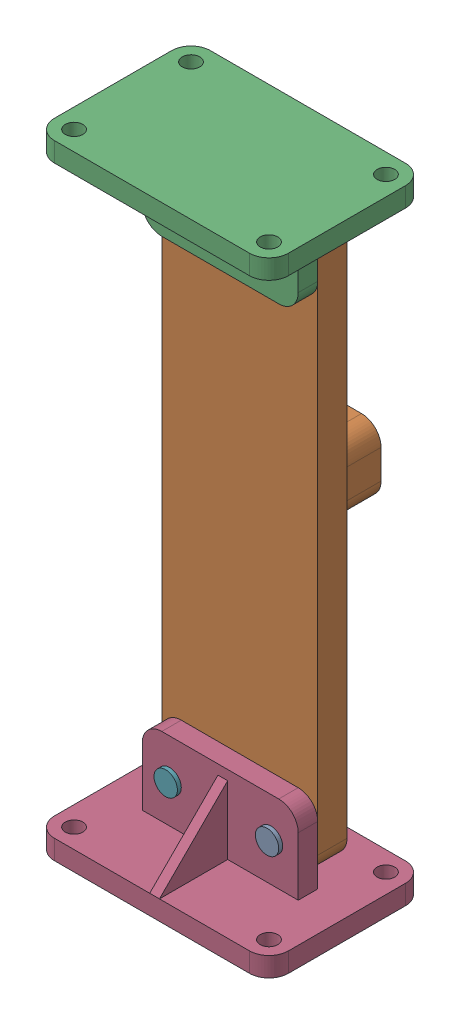
SolidWorks assembly Assem3, configuration Default. Lengths in mm.
Overall size (120 320 100).
6 component instances, 3 part files, 13 mates.
Components (placement in the parent):
- Part2-1: Part2 [Default] at (-1.9438 9.057 4.1149) size (12 12 29)
- Part3-1: Part3 [Default] at (-27.9438 139.057 4.1149) x (0 1 0) z (1 0 0) size (290 55 80)
- Part5withRib-1: Part5withRib [Default] at (-27.9438 -10.943 24.1149) x (-1 0 0) z (0 0 1) size (120 320 80)
- Part2-2: Part2 [Default] at (-1.9438 269.057 4.1149) size (12 12 29)
- Part2-3: Part2 [Default] at (-53.9438 269.057 4.1149) size (12 12 29)
- Part2-4: Part2 [Default] at (-53.9438 9.057 4.1149) size (12 12 29)
Mates (geometry in assembly coordinates):
- Concentric1: concentric aligned: cylinder of Part3-1 through (-53.9438 269.057 4.1149) axis (0 0 1) radius 4.5; cylinder of Part5withRib-1 through (-53.9438 269.057 -15.8851) axis (0 0 1) radius 4.5
- Concentric2: concentric aligned: cylinder of Part3-1 through (-1.9438 269.057 4.1149) axis (0 0 1) radius 4.5; cylinder of Part5withRib-1 through (-1.9438 269.057 -15.8851) axis (0 0 1) radius 4.5
- Concentric3: concentric aligned: cylinder of Part3-1 through (-1.9438 9.057 4.1149) axis (0 0 1) radius 4.5; cylinder of Part5withRib-1 through (-1.9438 9.057 -15.8851) axis (0 0 1) radius 4.5
- Concentric4: concentric aligned: cylinder of Part3-1 through (-53.9438 9.057 4.1149) axis (0 0 1) radius 4.5; cylinder of Part5withRib-1 through (-53.9438 9.057 -15.8851) axis (0 0 1) radius 4.5
- Coincident1: coincident anti-aligned: plane of Part3-1 through (-27.9438 139.057 19.1149) normal (0 0 1); plane of Part5withRib-1 through (-67.9438 29.057 19.1149) normal (0 0 -1)
- Concentric5: concentric anti-aligned: cylinder of Part2-1 through (-1.9438 9.057 29.1149) axis (0 0 -1) radius 4.5; cylinder of Part3-1 through (-1.9438 9.057 4.1149) axis (0 0 1) radius 4.5
- Coincident2: coincident anti-aligned: plane of Part2-1 through (-1.9438 9.057 29.1149) normal (0 0 -1); plane of Part5withRib-1 through (-67.9438 29.057 29.1149) normal (0 0 1)
- Concentric6: concentric anti-aligned: cylinder of Part3-1 through (-1.9438 269.057 4.1149) axis (0 0 1) radius 4.5; cylinder of Part2-2 through (-1.9438 269.057 29.1149) axis (0 0 -1) radius 4.5
- Coincident3: coincident anti-aligned: plane of Part3-1 through (-27.9438 139.057 4.1149) normal (0 0 -1); plane of Part2-2 through (-1.9438 269.057 4.1149) normal (0 0 1)
- Concentric7: concentric anti-aligned: cylinder of Part3-1 through (-53.9438 269.057 4.1149) axis (0 0 1) radius 4.5; cylinder of Part2-3 through (-53.9438 269.057 29.1149) axis (0 0 -1) radius 4.5
- Coincident4: coincident anti-aligned: plane of Part3-1 through (-27.9438 139.057 4.1149) normal (0 0 -1); plane of Part2-3 through (-53.9438 269.057 4.1149) normal (0 0 1)
- Concentric8: concentric anti-aligned: cylinder of Part3-1 through (-53.9438 9.057 4.1149) axis (0 0 1) radius 4.5; cylinder of Part2-4 through (-53.9438 9.057 29.1149) axis (0 0 -1) radius 4.5
- Coincident5: coincident anti-aligned: plane of Part3-1 through (-27.9438 139.057 4.1149) normal (0 0 -1); plane of Part2-4 through (-53.9438 9.057 4.1149) normal (0 0 1)
